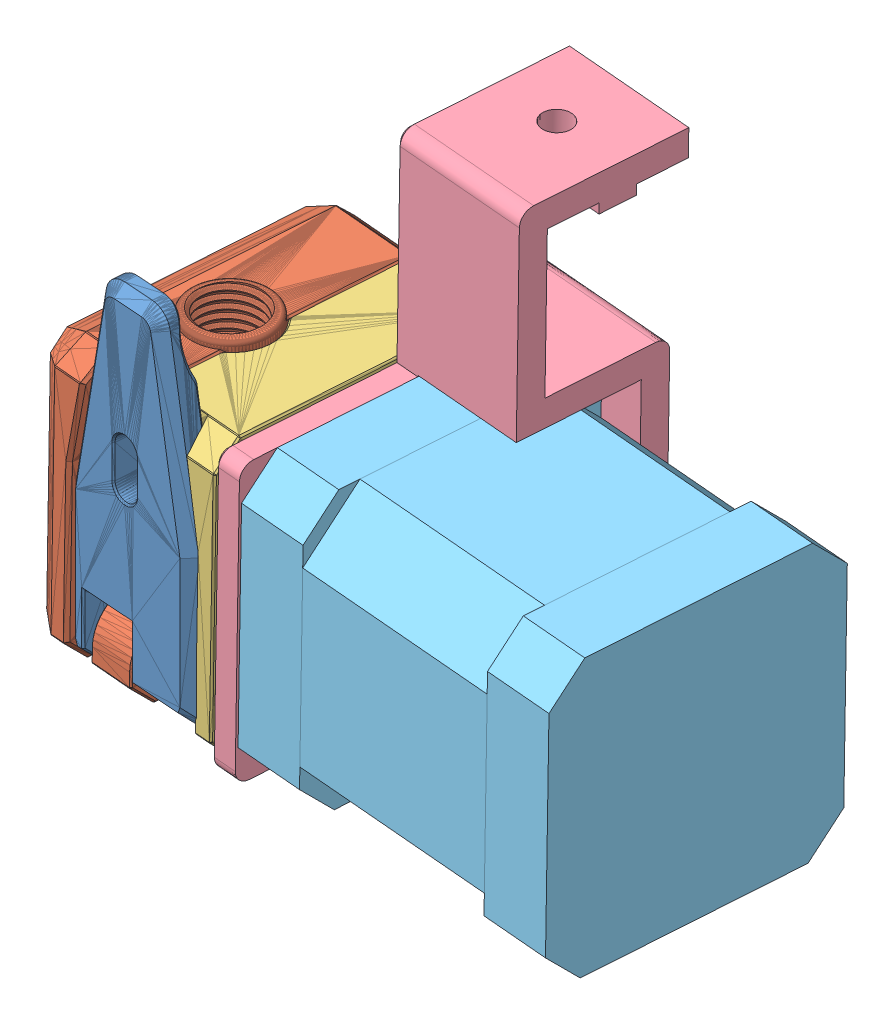
SolidWorks assembly Bondtech_extruder_alt, configuration Default. Lengths in mm.
Overall size (86.45 73.82 52.55).
5 component instances, 5 part files, 12 mates.
Components (placement in the parent):
- Bondtech_arm-1: Bondtech_arm [Default] at (594.2842 355.0346 -89.1644) x (-0.000002 1 0.000028) z (0.069756 0.000028 -0.997564) size (55 20 18)
- bondtech_bot-1: bondtech_bot [Default] at (654.0473 445.909 5.5666) x (0.068216 0.000091 -0.997671) z (0.997515 -0.017664 0.068204) size (42.5 43.5 19)
- bondtech_top-1: bondtech_top [Default] at (698.1084 430.1483 -217.7356) x (-0.068216 -0.000091 0.997671) z (-0.997515 0.017664 -0.068204) size (42.5 42.5 13)
- motor_mount-1: motor_mount [Default] at (692.9645 491.4813 -126.6187) x (0.068216 0.000091 -0.997671) z (0.997515 -0.017664 0.068204) size (49.28 72.88 20)
- DummyNema17.step-1-1: DummyNema17.step-1 [Default] at (746.8064 490.5274 -122.5865) x (0.017617 0.999844 0.001296) z (-0.068216 -0.000091 0.997671) size (42.3 72 42.3)
Mates (geometry in assembly coordinates):
- Coincident103: coincident: plane of Bondtech_arm-1 through (589.8606 399.4386 -25.9036) normal (0.057141 -0.573577 -0.817156); line of bondtech_top-1 through (690.256 498.1909 -88.1993) axis (-0.053558 -0.819076 0.57118)
- Coincident104: coincident aligned: plane of Bondtech_arm-1 through (595.515 356.5785 -106.7658) normal (0.069491 0.087167 -0.993767); plane of bondtech_top-1 through (689.504 419.3552 -94.687) normal (0.069491 0.087167 -0.993767)
- Coincident109: coincident: point of Bondtech_arm-1; plane of bondtech_top-1 through (695.6146 430.1925 -217.9061) normal (-0.997515 0.017664 -0.068204)
- Width76: width anti-aligned: plane of bondtech_top-1 through (699.9362 533.883 -217.6012) normal (0.017617 0.999844 0.001296); plane of bondtech_top-1 through (699.1874 491.3896 -217.6562) normal (-0.017617 -0.999844 -0.001296); plane of bondtech_bot-1 through (654.8573 491.8813 5.6262) normal (-0.017617 -0.999844 -0.001296); plane of bondtech_bot-1 through (655.606 534.3747 5.6813) normal (0.017617 0.999844 0.001296)
- Width77: width anti-aligned: plane of bondtech_top-1 through (691.8496 430.14 -126.1993) normal (0.068216 0.000091 -0.997671); plane of bondtech_top-1 through (688.9504 430.1361 -83.7983) normal (-0.068216 -0.000091 0.997671); plane of bondtech_bot-1 through (660.2915 445.9173 -85.7564) normal (-0.068216 -0.000091 0.997671); plane of bondtech_bot-1 through (663.1907 445.9212 -128.1574) normal (0.068216 0.000091 -0.997671)
- Coincident100: coincident anti-aligned: plane of bondtech_bot-1 through (670.0075 445.6264 6.6579) normal (0.997515 -0.017664 0.068204); plane of bondtech_top-1 through (685.1407 430.3779 -218.6223) normal (-0.997515 0.017664 -0.068204)
- Coincident110: coincident anti-aligned: plane of bondtech_top-1 through (698.1084 430.1483 -217.7356) normal (0.997515 -0.017664 0.068204); plane of motor_mount-1 through (692.9645 491.4813 -126.6187) normal (-0.997515 0.017664 -0.068204)
- Width78: width anti-aligned: plane of motor_mount-1 through (713.1877 491.1284 -129.2453) normal (-0.017617 -0.999844 -0.001296); plane of bondtech_top-1 through (697.6998 533.704 -126.291) normal (0.017617 0.999844 0.001296); plane of motor_mount-1 through (699.9362 533.883 -217.6012) normal (0.017617 0.999844 0.001296); plane of bondtech_top-1 through (699.1874 491.3896 -217.6562) normal (-0.017617 -0.999844 -0.001296)
- Coincident111: coincident aligned: plane of bondtech_top-1 through (688.9504 430.1361 -83.7983) normal (-0.068216 -0.000091 0.997671); plane of motor_mount-1 through (694.0213 491.4067 -83.446) normal (-0.068216 -0.000091 0.997671)
- Concentric1: concentric anti-aligned: cylinder of motor_mount-1 through (695.0762 528.0516 -89.3845) axis (-0.997515 0.017664 -0.068204) radius 1.6; cylinder of DummyNema17.step-1-1 through (695.0762 528.0516 -89.3845) axis (0.997515 -0.017664 0.068204) radius 1.5
- Parallel1: parallel aligned: plane of motor_mount-1 through (694.0213 491.4067 -83.446) normal (-0.068216 -0.000091 0.997671); plane of DummyNema17.step-1-1 through (704.0203 491.2301 -83.1132) normal (-0.068216 -0.000091 0.997671)
- Coincident113: coincident anti-aligned: plane of motor_mount-1 through (696.9546 491.4106 -126.3458) normal (0.997515 -0.017664 0.068204); plane of DummyNema17.step-1-1 through (695.8605 512.5554 -104.8685) normal (-0.997515 0.017664 -0.068204)
